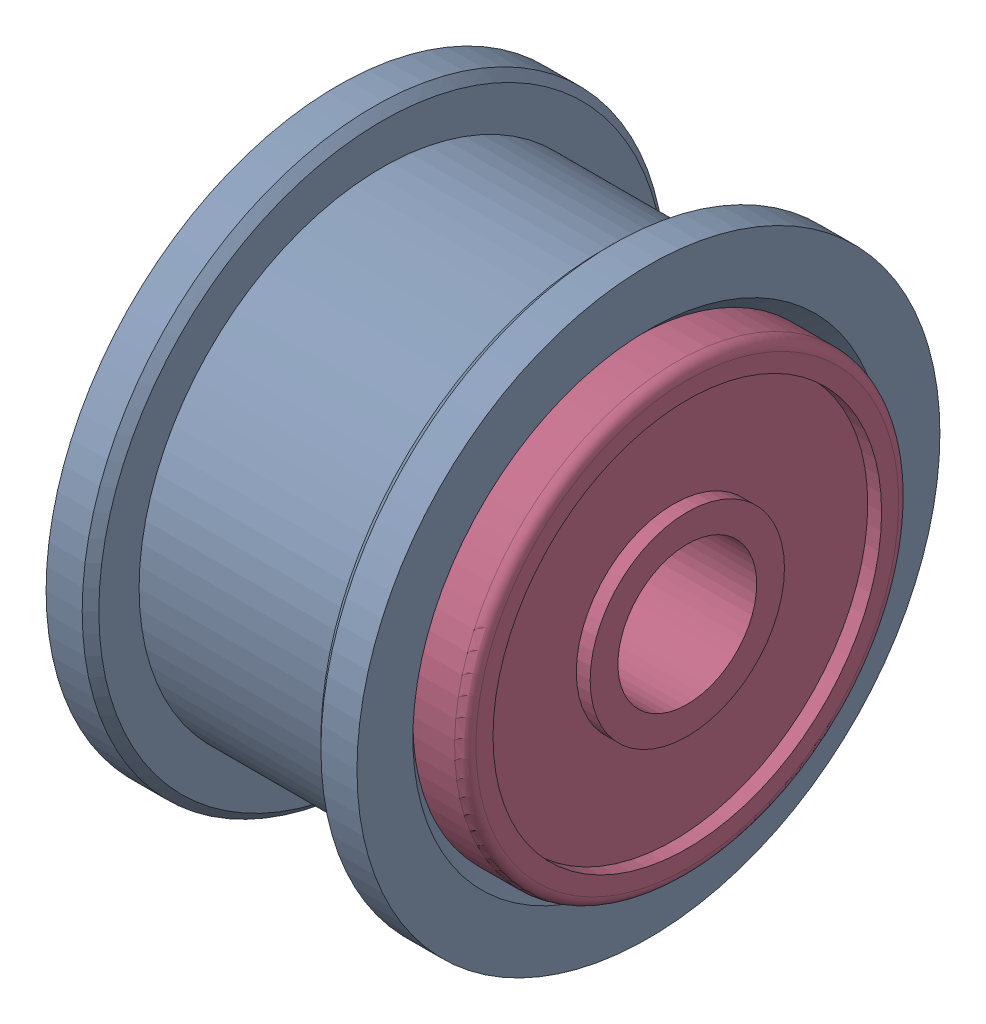
SolidWorks assembly B30041_ASM, configuration Default. Lengths in mm.
Overall size (12.6 21 21).
4 component instances, 3 part files, 0 mates.
Components (placement in the parent):
- B17023-1: B17023 [Default] at origin size (11.2 21 21)
- BEARING_5_16_5-1: BEARING_5_16_5 [Default] at (-1.5 0 0) x (0 1 0) z (0 0 1) size (16 5 16)
- B18026-1: B18026 [Default] at (2 0 0) x (0 1 0) z (0 0 1) size (10 1 10)
- BEARING_5_16_5-2: BEARING_5_16_5 [Default] at (4.5 0 0) x (0 1 0) z (0 0 1) size (16 5 16)
